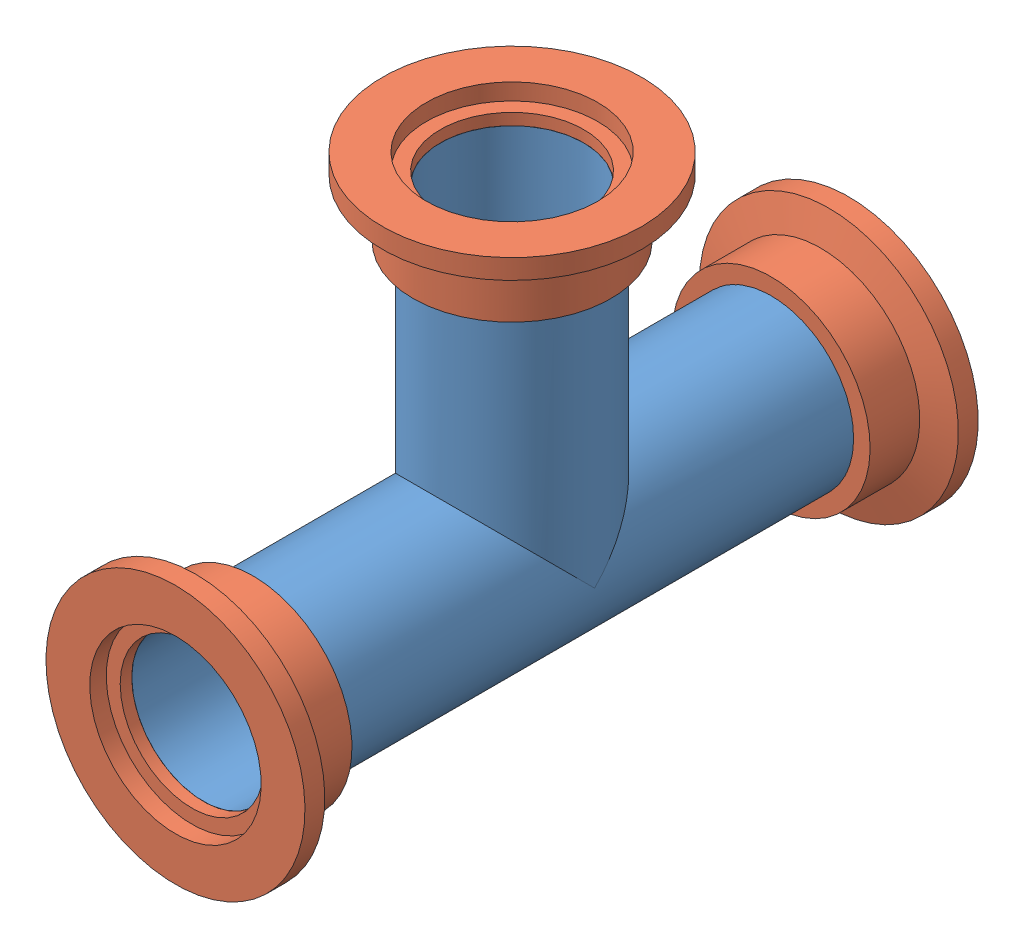
SolidWorks assembly 724001, configuration Default. Lengths in mm.
Overall size (50.51 77.07 103.63).
4 component instances, 2 part files, 3 mates.
Components (placement in the parent):
- 404501-1: 404501 [Default] at (50.2437 37.33 61.6139) size (25.4 60.2 95)
- 713002-1: 713002 [Default] at (50.2437 37.33 9.7979) x (-0.086548 -0.996248 0) z (0 0 1) size (39.88 39.88 11.94)
- 713002-2: 713002 [Default] at (50.2437 37.33 113.4299) x (0.947789 0.318897 0) z (0 0 -1) size (39.88 39.88 11.94)
- 713002-3: 713002 [Default] at (50.2437 89.146 61.6139) x (-0.259486 0 0.965747) z (0 -1 0) size (39.88 39.88 11.94)
Mates (geometry in assembly coordinates):
- Coincident1: coincident anti-aligned: circle of 404501-1; circle of 713002-1
- Coincident2: coincident aligned: circle of 404501-1; circle of 713002-2
- Coincident3: coincident aligned: circle of 404501-1; circle of 713002-3
